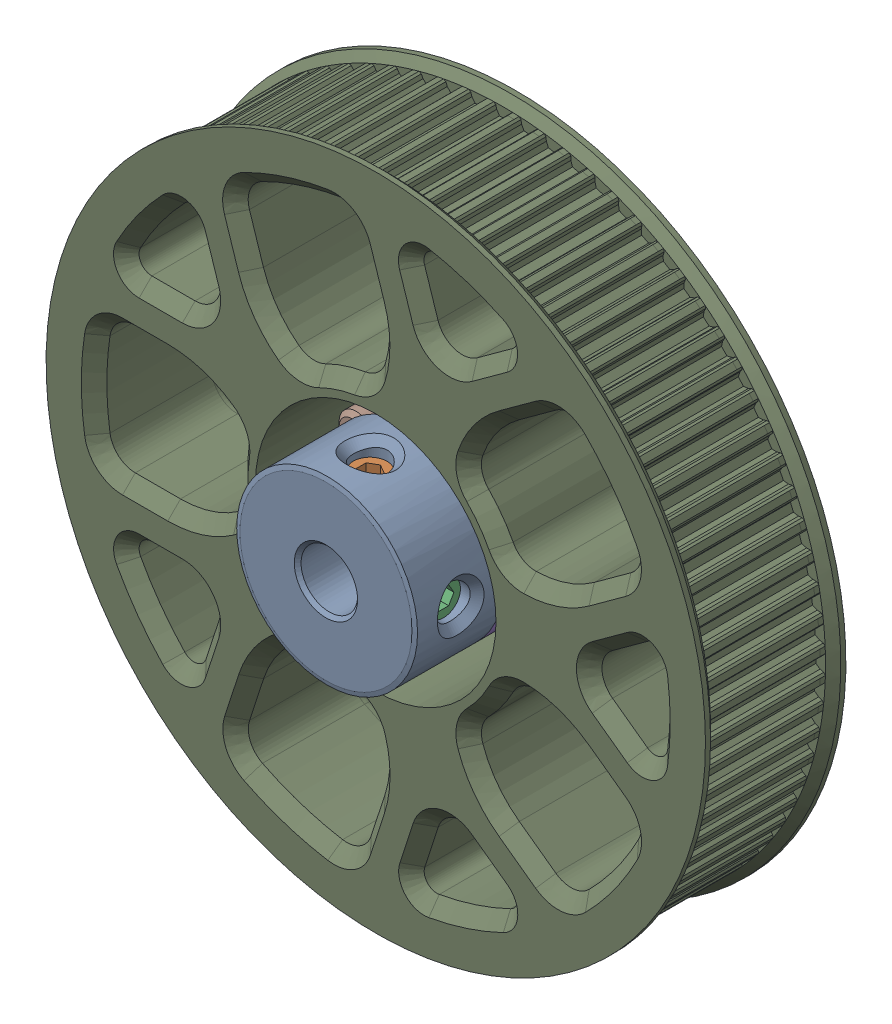
SolidWorks assembly 80T Gear v1, configuration Varsayılan. Lengths in mm.
Overall size (58.34 58.34 17.85).
7 component instances, 3 part files, 0 mates.
Components (placement in the parent):
- GT2 20T 6mm Powge v2 (1)-1: GT2 20T 6mm Powge v2 (1) [Varsayılan] at (-0.0006 -0.0003 11.2993) x (0 0 -1) z (1 0 0) size (16 16 16)
- M3x8 BHCS-1: M3x8 BHCS [Varsayılan] at (-5.9041 -4.2895 -6.5507) x (-1 0 0) z (0 0 -1) size (5.7 5.7 9.65)
- M3x8 BHCS-2: M3x8 BHCS [Varsayılan] at (2.2544 -6.9404 -6.5507) x (-0.309017 -0.951057 0) z (0 0 -1) size (5.7 5.7 9.65)
- M3x8 BHCS-3: M3x8 BHCS [Varsayılan] at (7.2966 -0.0003 -6.5507) x (0.809017 -0.587785 0) z (0 0 -1) size (5.7 5.7 9.65)
- M3x8 BHCS-4: M3x8 BHCS [Varsayılan] at (2.2544 6.9397 -6.5507) x (0.809017 0.587785 0) z (0 0 -1) size (5.7 5.7 9.65)
- M3x8 BHCS-5: M3x8 BHCS [Varsayılan] at (-5.9041 4.2888 -6.5507) x (-0.309017 0.951057 0) z (0 0 -1) size (5.7 5.7 9.65)
- 80T Gear v1-0-1: 80T Gear v1-0 [Varsayılan] at origin size (58.34 58.34 12.51)
